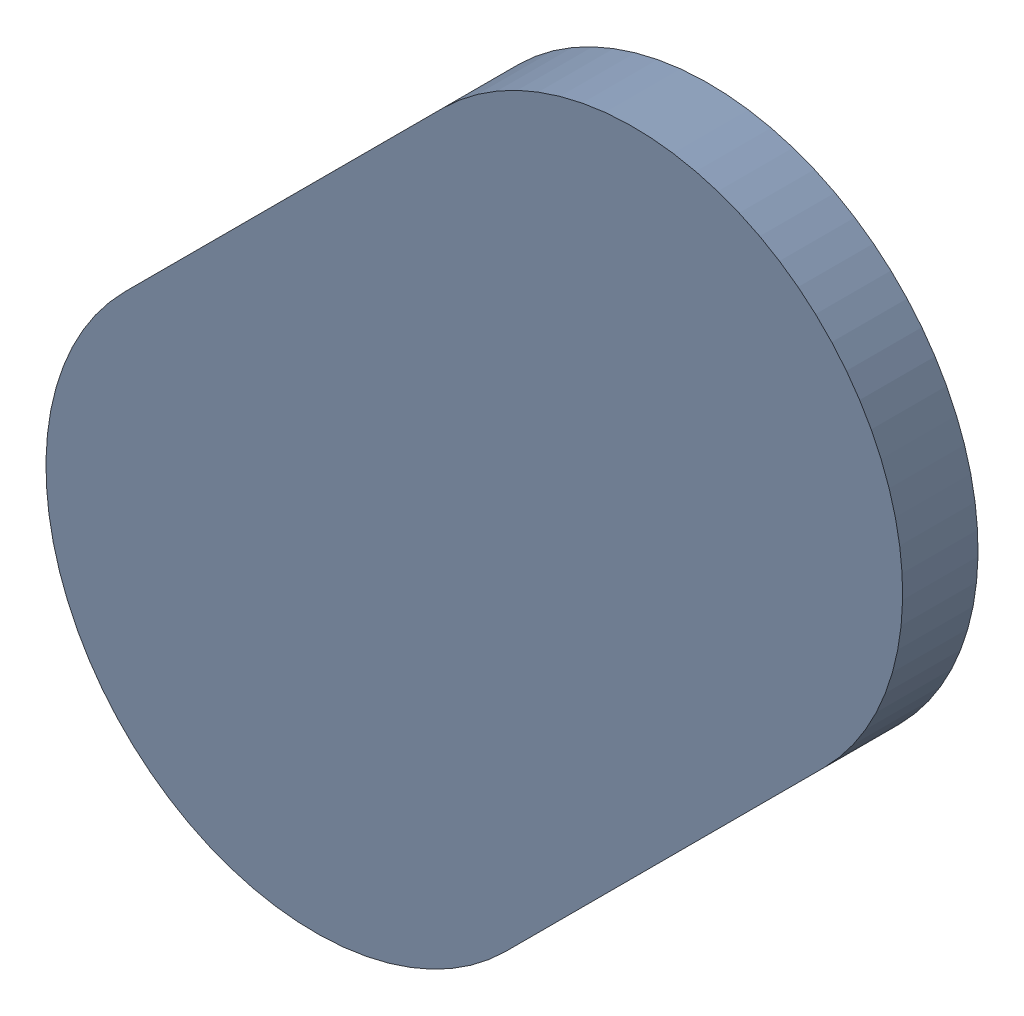
SolidWorks assembly Track (31.65mm,40mm)(31.8mm,40.15mm) on Top Layer, configuration Predeterminado. Lengths in mm.
Overall size (0.4 0.4 0.04).
2 component instances, 1 part files, 0 mates.
Components (placement in the parent):
- Track (31.65mm,40mm)(31.8mm,40.15mm) on Top Layer-1-1: Track (31.65mm,40mm)(31.8mm,40.15mm) on Top Layer-1 [Predeterminado] at (-68.317 -44.187 -0.0457) size (0.4 0.4 0.04)
  - Track (31.65mm,40mm)(31.8mm,40.15mm) on Top Layer-Part-1-1: Track (31.65mm,40mm)(31.8mm,40.15mm) on Top Layer-Part-1 [Predeterminado] at origin size (0.4 0.4 0.04)
